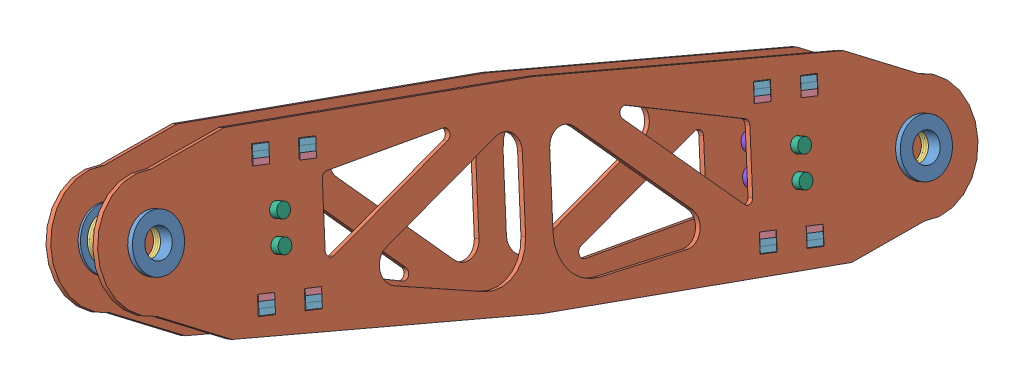
SolidWorks assembly j3, configuration 默认. Lengths in mm.
Overall size (85.84 160.68 325.29).
54 component instances, 8 part files, 28 mates.
Components (placement in the parent):
- 法兰轴承10-19-5-金鑫莱-1_6-1: 法兰轴承10-19-5-金鑫莱-1_6 [默认] at (-48.1731 71.632 -324.5774) x (0.177614 -0.411183 -0.894082) z (-0.918016 -0.396544 0) size (21 21 5)
- 垂直板2-1: 垂直板2 [默认] at (-3.9115 14.5568 -522.6173) x (-0.375603 0.869537 -0.320668) z (0.918016 0.396544 0) size (66.06 321.06 2)
- 垂直板2-2: 垂直板2 [默认] at (-22.5006 12.199 -524.3801) x (0.375603 -0.869537 0.320668) z (-0.918016 -0.396544 0) size (66.06 321.06 2)
- 法兰轴承10-19-5-金鑫莱-1_6-2: 法兰轴承10-19-5-金鑫莱-1_6 [默认] at (-31.6488 78.7698 -324.5774) x (-0.195299 0.452125 0.870311) z (0.918016 0.396544 0) size (21 21 5)
- M10垫片16-1-1: M10垫片16-1 [默认] at (-46.337 72.4251 -324.5774) x (-0.081512 0.188703 0.978645) z (-0.918016 -0.396544 0) size (16 16 1)
- M10垫片16-1-2: M10垫片16-1 [默认] at (-45.419 72.8216 -324.5774) x (-0.346292 0.801681 -0.487226) z (-0.918016 -0.396544 0) size (16 16 1)
- M10垫片16-1-3: M10垫片16-1 [默认] at (-44.501 73.2181 -324.5774) x (0.085341 -0.197568 0.976567) z (-0.918016 -0.396544 0) size (16 16 1)
- M10垫片16-1-4: M10垫片16-1 [默认] at (-32.5668 78.3732 -324.5774) x (-0.081512 0.188703 0.978645) z (-0.918016 -0.396544 0) size (16 16 1)
- M10垫片16-1-5: M10垫片16-1 [默认] at (-33.4848 77.9767 -324.5774) x (-0.081512 0.188703 0.978645) z (-0.918016 -0.396544 0) size (16 16 1)
- M10垫片16-1-6: M10垫片16-1 [默认] at (-34.4028 77.5801 -324.5774) x (-0.081512 0.188703 0.978645) z (-0.918016 -0.396544 0) size (16 16 1)
- 线口板-1: 线口板 [默认] at (-78.8919 135.9278 -404.1025) x (0.900391 0.434848 -0.014271) z (0.127159 -0.294379 -0.947192) size (22.35 6.98 23.1)
  - 线口板-1: 线口板 [默认] at (-3.3196 112.811 -12.4421) x (0 0 1) z (0.044504 -0.999009 0) size (23.1 22.1 2)
  - 线口板-M4孔-1: 线口板-M4孔 [默认] at (-3.4086 114.809 -12.4421) x (0 0 1) z (0.044504 -0.999009 0) size (23.1 22.1 2)
  - 线口板-M4孔-2: 线口板-M4孔 [默认] at (-3.4976 116.807 -12.4421) x (0 0 1) z (0.044504 -0.999009 0) size (23.1 22.1 2)
- 线口板-2: 线口板 [默认] at (-10.0595 -23.4222 -337.1192) x (0.933822 0.357453 0.014271) z (-0.127159 0.294379 0.947192) size (22.35 6.98 23.1)
  - 线口板-1: 线口板 [默认] at (-3.3196 112.811 -12.4421) x (0 0 1) z (0.044504 -0.999009 0) size (23.1 22.1 2)
  - 线口板-M4孔-1: 线口板-M4孔 [默认] at (-3.4086 114.809 -12.4421) x (0 0 1) z (0.044504 -0.999009 0) size (23.1 22.1 2)
  - 线口板-M4孔-2: 线口板-M4孔 [默认] at (-3.4976 116.807 -12.4421) x (0 0 1) z (0.044504 -0.999009 0) size (23.1 22.1 2)
- 线口板-5: 线口板 [默认] at (13.1852 -77.2347 -510.2658) x (0.933822 0.357453 0.014271) z (-0.127159 0.294379 0.947192) size (22.35 6.98 23.1)
  - 线口板-1: 线口板 [默认] at (-3.3196 112.811 -12.4421) x (0 0 1) z (0.044504 -0.999009 0) size (23.1 22.1 2)
  - 线口板-M4孔-1: 线口板-M4孔 [默认] at (-3.4086 114.809 -12.4421) x (0 0 1) z (0.044504 -0.999009 0) size (23.1 22.1 2)
  - 线口板-M4孔-2: 线口板-M4孔 [默认] at (-3.4976 116.807 -12.4421) x (0 0 1) z (0.044504 -0.999009 0) size (23.1 22.1 2)
- 线口板-6: 线口板 [默认] at (-55.6472 82.1154 -577.2492) x (0.900391 0.434848 -0.014271) z (0.127159 -0.294379 -0.947192) size (22.35 6.98 23.1)
  - 线口板-1: 线口板 [默认] at (-3.3196 112.811 -12.4421) x (0 0 1) z (0.044504 -0.999009 0) size (23.1 22.1 2)
  - 线口板-M4孔-1: 线口板-M4孔 [默认] at (-3.4086 114.809 -12.4421) x (0 0 1) z (0.044504 -0.999009 0) size (23.1 22.1 2)
  - 线口板-M4孔-2: 线口板-M4孔 [默认] at (-3.4976 116.807 -12.4421) x (0 0 1) z (0.044504 -0.999009 0) size (23.1 22.1 2)
- M10垫片16-1-13: M10垫片16-1 [默认] at (-8.8965 -9.2079 -589.791) x (0.085341 -0.197568 0.976567) z (-0.918016 -0.396544 0) size (16 16 1)
- M10垫片16-1-14: M10垫片16-1 [默认] at (-9.8145 -9.6044 -589.791) x (-0.346292 0.801681 -0.487226) z (-0.918016 -0.396544 0) size (16 16 1)
- M10垫片16-1-15: M10垫片16-1 [默认] at (-10.7325 -10.001 -589.791) x (-0.081512 0.188703 0.978645) z (-0.918016 -0.396544 0) size (16 16 1)
- 法兰轴承10-19-5-金鑫莱-1_6-5: 法兰轴承10-19-5-金鑫莱-1_6 [默认] at (-12.5685 -10.7941 -589.791) x (0.177614 -0.411183 -0.894082) z (-0.918016 -0.396544 0) size (21 21 5)
- M10垫片16-1-16: M10垫片16-1 [默认] at (0.2837 -5.2425 -589.791) x (-0.150645 0.34875 -0.925029) z (0.918016 0.396544 0) size (16 16 1)
- M10垫片16-1-17: M10垫片16-1 [默认] at (1.2017 -4.8459 -589.791) x (-0.174371 0.403676 0.898132) z (0.918016 0.396544 0) size (16 16 1)
- M10垫片16-1-18: M10垫片16-1 [默认] at (2.1197 -4.4494 -589.791) x (-0.2882 0.667196 -0.686869) z (0.918016 0.396544 0) size (16 16 1)
- 法兰轴承10-19-5-金鑫莱-1_6-6: 法兰轴承10-19-5-金鑫莱-1_6 [默认] at (3.9558 -3.6563 -589.791) x (0.357938 -0.828642 0.430388) z (0.918016 0.396544 0) size (21 21 5)
- 光轴柱-1: 光轴柱 [默认] at (37.7229 -59.4483 -553.4773) x (0.726564 0.687099 0) z (0 0 1) size (28.47 15.53 9.86)
  - M5光轴对线用-1: M5光轴对线用 [默认] at (21.8197 71.1318 7.9133) x (0.325138 0.891437 0.315635) z (-0.939462 0.342654 0) size (5 5 28)
  - 铜套5-7-10-1: 铜套5-7-10 [默认] at (13.3646 74.2157 7.9133) x (0.218976 0.600371 0.769158) z (-0.939462 0.342654 0) size (7 7 10)
  - 铜套5-7-4-1: 铜套5-7-4 [默认] at (17.1224 72.8451 7.9133) x (0.338822 0.928955 0.149138) z (-0.939462 0.342654 0) size (7 7 4)
  - 铜套5-7-4-2: 铜套5-7-4 [默认] at (3.97 77.6422 7.9133) x (0.197516 0.541533 -0.817147) z (-0.939462 0.342654 0) size (7 7 4)
- 光轴柱-2: 光轴柱 [默认] at (33.9669 -50.7529 -556.684) x (0.726564 0.687099 0) z (0 0 1) size (28.47 15.53 9.86)
  - M5光轴对线用-1: M5光轴对线用 [默认] at (21.8197 71.1318 7.9133) x (0.325138 0.891437 0.315635) z (-0.939462 0.342654 0) size (5 5 28)
  - 铜套5-7-10-1: 铜套5-7-10 [默认] at (13.3646 74.2157 7.9133) x (0.218976 0.600371 0.769158) z (-0.939462 0.342654 0) size (7 7 10)
  - 铜套5-7-4-1: 铜套5-7-4 [默认] at (17.1224 72.8451 7.9133) x (0.338822 0.928955 0.149138) z (-0.939462 0.342654 0) size (7 7 4)
  - 铜套5-7-4-2: 铜套5-7-4 [默认] at (3.97 77.6422 7.9133) x (0.197516 0.541533 -0.817147) z (-0.939462 0.342654 0) size (7 7 4)
- 光轴柱-3: 光轴柱 [默认] at (9.8066 5.179 -376.7176) x (0.726564 0.687099 0) z (0 0 1) size (28.47 15.53 9.86)
  - M5光轴对线用-1: M5光轴对线用 [默认] at (21.8197 71.1318 7.9133) x (0.325138 0.891437 0.315635) z (-0.939462 0.342654 0) size (5 5 28)
  - 铜套5-7-10-1: 铜套5-7-10 [默认] at (13.3646 74.2157 7.9133) x (0.218976 0.600371 0.769158) z (-0.939462 0.342654 0) size (7 7 10)
  - 铜套5-7-4-1: 铜套5-7-4 [默认] at (17.1224 72.8451 7.9133) x (0.338822 0.928955 0.149138) z (-0.939462 0.342654 0) size (7 7 4)
  - 铜套5-7-4-2: 铜套5-7-4 [默认] at (3.97 77.6422 7.9133) x (0.197516 0.541533 -0.817147) z (-0.939462 0.342654 0) size (7 7 4)
- 光轴柱-5: 光轴柱 [默认] at (13.5627 -3.5164 -373.5109) x (0.726564 0.687099 0) z (0 0 1) size (28.47 15.53 9.86)
  - M5光轴对线用-1: M5光轴对线用 [默认] at (21.8197 71.1318 7.9133) x (0.325138 0.891437 0.315635) z (-0.939462 0.342654 0) size (5 5 28)
  - 铜套5-7-10-1: 铜套5-7-10 [默认] at (13.3646 74.2157 7.9133) x (0.218976 0.600371 0.769158) z (-0.939462 0.342654 0) size (7 7 10)
  - 铜套5-7-4-1: 铜套5-7-4 [默认] at (17.1224 72.8451 7.9133) x (0.338822 0.928955 0.149138) z (-0.939462 0.342654 0) size (7 7 4)
  - 铜套5-7-4-2: 铜套5-7-4 [默认] at (3.97 77.6422 7.9133) x (0.197516 0.541533 -0.817147) z (-0.939462 0.342654 0) size (7 7 4)
Mates (geometry in assembly coordinates):
- 重合77: coincident anti-aligned: circle of 法兰轴承10-19-5-金鑫莱-1_6-1; circle of M10垫片16-1-1
- 重合78: coincident aligned: circle of M10垫片16-1-2; circle of M10垫片16-1-3
- 重合79: coincident aligned: circle of M10垫片16-1-1; circle of M10垫片16-1-2
- 重合80: coincident aligned: circle of M10垫片16-1-5; circle of M10垫片16-1-6
- 重合81: coincident aligned: circle of M10垫片16-1-4; circle of M10垫片16-1-5
- 重合82: coincident aligned: circle of 法兰轴承10-19-5-金鑫莱-1_6-2; circle of M10垫片16-1-4
- 同心37: concentric aligned: cylinder of 法兰轴承10-19-5-金鑫莱-1_6-1 through (-51.8451 70.0458 -324.5774) axis (0.918016 0.396544 0) radius 9.5; cylinder of 垂直板2-2 through (-50.0091 70.8389 -324.5774) axis (0.918016 0.396544 0) radius 9.55
- 重合85: coincident aligned: plane of 法兰轴承10-19-5-金鑫莱-1_6-1; plane of 垂直板2-2 through (-22.5006 12.199 -524.3801) normal (0.918016 0.396544 0)
- 同心38: concentric aligned: cylinder of 垂直板2-1 through (-29.8127 79.5628 -324.5774) axis (-0.918016 -0.396544 0) radius 9.55; cylinder of 法兰轴承10-19-5-金鑫莱-1_6-2 through (-27.9767 80.3559 -324.5774) axis (-0.918016 -0.396544 0) radius 9.5
- 重合86: coincident anti-aligned: plane of 垂直板2-1 through (-3.9115 14.5568 -522.6173) normal (-0.918016 -0.396544 0); plane of 法兰轴承10-19-5-金鑫莱-1_6-2 through (-31.6488 78.7698 -324.5774) normal (0.918016 0.396544 0)
- 重合95: coincident anti-aligned: circle of M10垫片16-1-15; circle of 法兰轴承10-19-5-金鑫莱-1_6-5
- 重合96: coincident aligned: circle of M10垫片16-1-13; circle of M10垫片16-1-14
- 重合97: coincident aligned: circle of M10垫片16-1-14; circle of M10垫片16-1-15
- 同心39: concentric aligned: cylinder of 垂直板2-2 through (-14.4046 -11.5872 -589.791) axis (0.918016 0.396544 0) radius 9.55; cylinder of 法兰轴承10-19-5-金鑫莱-1_6-5 through (-16.2406 -12.3802 -589.791) axis (0.918016 0.396544 0) radius 9.5
- 重合98: coincident anti-aligned: plane of 垂直板2-2 through (-22.5006 12.199 -524.3801) normal (0.918016 0.396544 0); plane of 法兰轴承10-19-5-金鑫莱-1_6-5 through (-12.5685 -10.7941 -589.791) normal (-0.918016 -0.396544 0)
- 重合99: coincident anti-aligned: circle of M10垫片16-1-18; circle of 法兰轴承10-19-5-金鑫莱-1_6-6
- 重合100: coincident aligned: circle of M10垫片16-1-16; circle of M10垫片16-1-17
- 重合101: coincident aligned: circle of M10垫片16-1-17; circle of M10垫片16-1-18
- 同心40: concentric aligned: cylinder of 垂直板2-1 through (5.7918 -2.8632 -589.791) axis (-0.918016 -0.396544 0) radius 9.55; cylinder of 法兰轴承10-19-5-金鑫莱-1_6-6 through (7.6278 -2.0701 -589.791) axis (-0.918016 -0.396544 0) radius 9.5
- 重合102: coincident anti-aligned: plane of 垂直板2-1 through (-3.9115 14.5568 -522.6173) normal (-0.918016 -0.396544 0); plane of 法兰轴承10-19-5-金鑫莱-1_6-6 through (3.9558 -3.6563 -589.791) normal (0.918016 0.396544 0)
- 同心45: concentric aligned: cylinder of 垂直板2-2 through (-18.2487 -2.6878 -545.564) axis (0.918016 0.396544 0) radius 2.55; cylinder of 光轴柱-1/M5光轴对线用-1 through (-21.0028 -3.8774 -545.564) axis (0.918016 0.396544 0) radius 2.5
- 重合108: coincident anti-aligned: plane of 垂直板2-2 through (-22.5006 12.199 -524.3801) normal (0.918016 0.396544 0); circle of 光轴柱-1/铜套5-7-4-2
- 同心46: concentric aligned: cylinder of 垂直板2-2 through (-22.0047 6.0076 -548.7707) axis (0.918016 0.396544 0) radius 2.55; cylinder of 光轴柱-2/M5光轴对线用-1 through (-24.7588 4.8179 -548.7707) axis (0.918016 0.396544 0) radius 2.5
- 重合109: coincident anti-aligned: plane of 垂直板2-2 through (-22.5006 12.199 -524.3801) normal (0.918016 0.396544 0); plane of 光轴柱-2/铜套5-7-4-2 through (-20.1687 6.8007 -548.7707) normal (-0.918016 -0.396544 0)
- 同心47: concentric aligned: cylinder of 垂直板2-2 through (-46.165 61.9395 -368.8043) axis (0.918016 0.396544 0) radius 2.55; cylinder of 光轴柱-3/M5光轴对线用-1 through (-48.919 60.7499 -368.8043) axis (0.918016 0.396544 0) radius 2.5
- 重合110: coincident anti-aligned: plane of 垂直板2-2 through (-22.5006 12.199 -524.3801) normal (0.918016 0.396544 0); plane of 光轴柱-3/铜套5-7-4-2 through (-44.3289 62.7326 -368.8043) normal (-0.918016 -0.396544 0)
- 同心48: concentric aligned: cylinder of 垂直板2-2 through (-42.4089 53.2442 -365.5976) axis (0.918016 0.396544 0) radius 2.55; cylinder of 光轴柱-5/M5光轴对线用-1 through (-45.163 52.0545 -365.5976) axis (0.918016 0.396544 0) radius 2.5
- 重合111: coincident anti-aligned: plane of 垂直板2-2 through (-22.5006 12.199 -524.3801) normal (0.918016 0.396544 0); plane of 光轴柱-5/铜套5-7-4-2 through (-40.5729 54.0372 -365.5976) normal (-0.918016 -0.396544 0)
